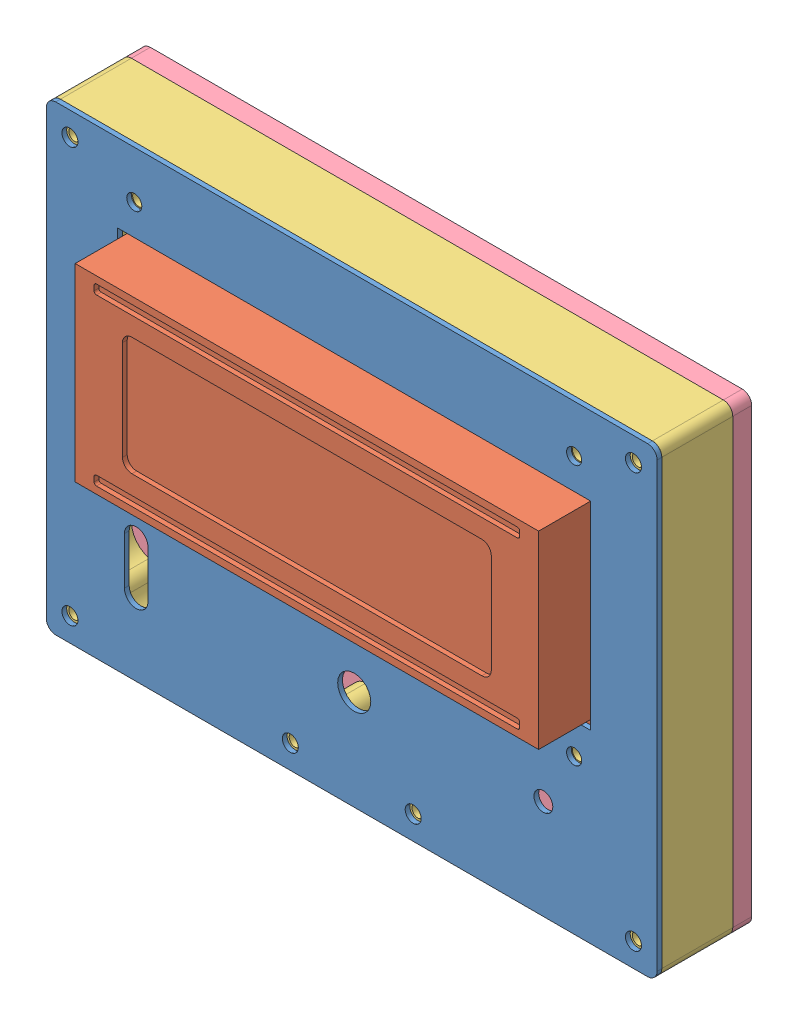
SolidWorks assembly New Panel Box, configuration Default. Lengths in mm.
Overall size (129.16 97.82 44.86).
4 component instances, 4 part files, 10 mates.
Components (placement in the parent):
- P0ANEL-1: P0ANEL [Default] at (8.066 80.2445 111.6053) size (129.16 97.62 1)
- lcd-1: lcd [Default] at (-30.4799 57.8649 102.6053) x (1 0 0) z (0 -1 0) size (98 15 60)
- panel case printed2-1: panel case printed2 [Default] at (0 0.4 120.6053) x (-1 0 0) z (0 0 -1) size (129.16 97.82 33.86)
- back cover-1: back cover [Default] at (0 0 96.6053) x (-1 0 0) z (0 0 -1) size (129.16 97.62 4)
Mates (geometry in assembly coordinates):
- Coincident1: coincident anti-aligned: plane of P0ANEL-1 through (118.5774 33.7875 111.6053) normal (0 0 -1); plane of lcd-1 through (105.5201 61.8649 109.6053) normal (0 0 1)
- Concentric1: concentric aligned: cylinder of P0ANEL-1 through (10.0201 119.3649 112.6053) axis (0 0 -1) radius 1.6001; cylinder of lcd-1 through (10.0201 119.3649 109.6053) axis (0 0 -1) radius 1.75
- Parallel4: parallel aligned: plane of P0ANEL-1 through (-6.5856 31.7875 112.6053) normal (0 -1 0); plane of lcd-1 through (105.5201 61.8649 109.6053) normal (0 -1 0)
- Concentric8: concentric aligned: cylinder of lcd-1 through (10.0201 64.3649 109.6053) axis (0 0 -1) radius 1.75; cylinder of panel case printed2-1 through (10.0201 64.3649 143.2952) axis (0 0 -1) radius 1.35
- Concentric9: concentric aligned: cylinder of lcd-1 through (103.0201 64.3649 109.6053) axis (0 0 -1) radius 1.75; cylinder of panel case printed2-1 through (103.0201 64.3649 143.2952) axis (0 0 -1) radius 1.35
- Coincident5: coincident anti-aligned: plane of P0ANEL-1 through (118.5774 33.7875 111.6053) normal (0 0 -1); plane of panel case printed2-1 through (120.5774 129.4077 111.6053) normal (0 0 1)
- Coincident22: coincident aligned: plane of panel case printed2-1 through (-6.5856 129.4077 96.6053) normal (0 1 0); plane of back cover-1 through (-6.5856 129.4077 92.6053) normal (0 1 0)
- Coincident23: coincident aligned: plane of panel case printed2-1 through (120.5774 127.4077 96.6053) normal (1 0 0); plane of back cover-1 through (120.5774 127.4077 92.6053) normal (1 0 0)
- Coincident26: coincident anti-aligned: plane of panel case printed2-1 through (-6.5856 127.4077 96.6053) normal (0 0 -1); plane of back cover-1 through (-6.5856 33.7875 96.6053) normal (0 0 1)
- Coincident27: coincident anti-aligned: plane of lcd-1 through (105.5201 61.8649 109.6053) normal (0 0 1); plane of panel case printed2-1 through (10.0201 64.3649 109.6053) normal (0 0 -1)
